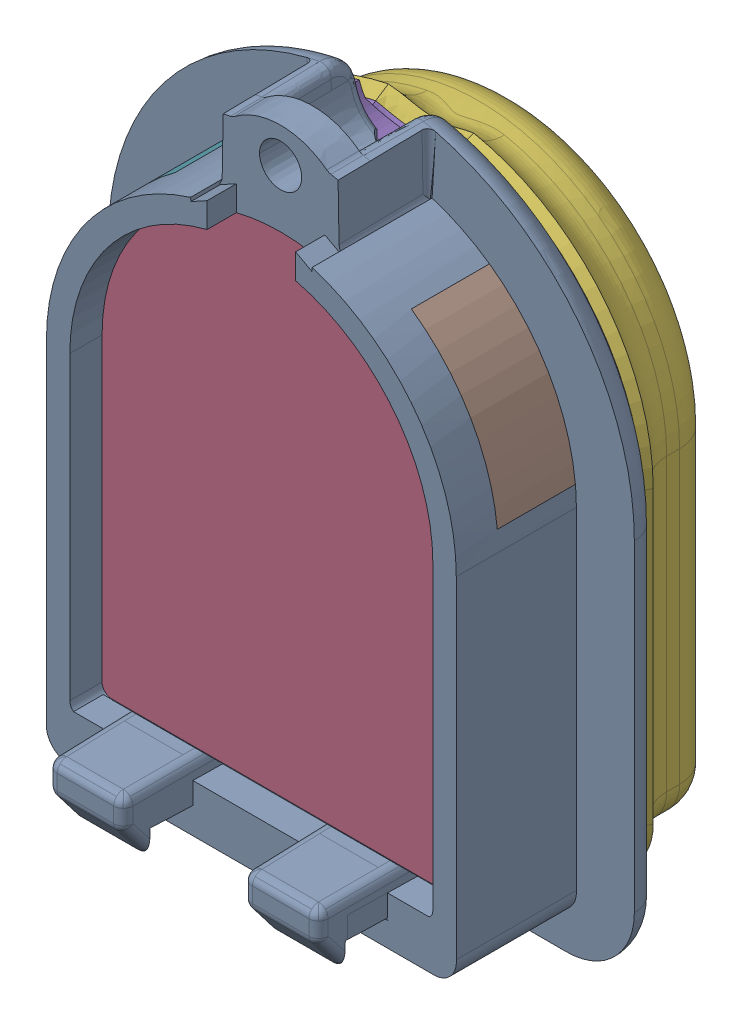
SolidWorks assembly Do2tDesign, configuration 默认. Lengths in mm.
Overall size (26.95 34.26 16.36).
9 component instances, 7 part files, 25 mates.
Components (placement in the parent):
- Dot2Tip1-1: Dot2Tip1 [默认] at (-1.9035 7.7463 -5.5591) size (26.95 34.26 11.2)
- Dot2lensnew-1: Dot2lensnew [默认] at (-1.9035 7.7463 -5.5591) size (18.6 25.2 6)
- Dot2Skin0.2-1: Dot2Skin0.2 [默认] at (-1.9035 7.4963 -5.5591) x (-1 0 0) z (0 0 -1) size (23.9 30.06 5.2)
- Dot2Skin1-1: Dot2Skin1 [默认] at (-1.9035 7.4963 -5.5591) x (-1 0 0) z (0 0 -1) size (22.77 29.32 5.25) (hidden)
- Dot2sidelens1-1: Dot2sidelens1 [默认] at (-1.9035 7.7463 -6.2091) size (6.4 7.71 4)
- Dot2sidelens1-2: Dot2sidelens1 [默认] at (-1.9035 7.7463 2.0909) x (-1 0 0) z (0 0 -1) size (6.4 7.71 4)
- Dot2bottomlens-1: Dot2bottomlens [默认] at (-5.9035 -10.5037 0.4409) x (1 0 0) z (0 1 0) size (8 4.5 2.35)
- Dot2DotMarker-1: Dot2DotMarker [默认] at (-7.9035 -5.4997 -10.2091) size (13 22 1)
- Dot2DotMarker-2: Dot2DotMarker [默认] at (-7.9035 -5.4997 -9.1991) size (13 22 1)
Mates (geometry in assembly coordinates):
- 同心1: concentric aligned: cylinder of Tip1-1 through (-1.9035 7.7463 51.2878) axis (0 0 -1) radius 9.3; cylinder of lensnew-1 through (-1.9035 7.7463 0.4409) axis (0 0 -1) radius 9.3
- 重合1: coincident anti-aligned: plane of Tip1-1 through (-1.9035 -8.1537 51.2878) normal (0 1 0); plane of lensnew-1 through (-11.2035 -8.1537 0.4409) normal (0 -1 0)
- 重合2: coincident aligned: plane of Tip1-1 through (-1.964 4.3089 -5.5591) normal (0 0 -1); plane of lensnew-1 through (-1.9035 7.7463 -5.5591) normal (0 0 -1)
- 重合3: coincident anti-aligned: plane of lensnew-1 through (-1.9035 7.7463 -5.5591) normal (0 0 -1); plane of Skin0.2-1 through (-1.9035 7.4963 -5.5591) normal (0 0 1)
- 同心2: concentric aligned: cone of Tip1-1 through (-1.9035 19.9963 -1.0591) axis (0 0 1); cylinder of Skin0.2-1 through (-1.9035 19.9963 -6.3091) axis (0 0 1) radius 2.75
- 宽度1: width aligned: plane of Skin0.2-1 through (-13.8535 7.4963 -5.5591) normal (-1 0 0); plane of Skin0.2-1 through (10.0465 7.4963 -5.5591) normal (1 0 0); plane of Tip1-1 through (-12.4035 7.7463 2.0909) normal (-1 0 0); plane of Tip1-1 through (8.5965 7.7463 2.0909) normal (1 0 0)
- 重合4: coincident anti-aligned: plane of Skin0.2-1 through (-1.9035 7.4963 -10.7591) normal (0 0 -1); plane of Skin1-1 through (-1.9035 7.4963 -10.7591) normal (0 0 1)
- 宽度2: width anti-aligned: plane of Skin0.2-1 through (-13.8535 7.4963 -5.5591) normal (-1 0 0); plane of Skin0.2-1 through (10.0465 7.4963 -5.5591) normal (1 0 0); plane of Skin1-1 through (-12.8325 0.0508 -6.2245) normal (-0.891007 0 0.45399); plane of Skin1-1 through (9.0255 0.0508 -6.2245) normal (0.891007 0 0.45399)
- 重合5: coincident aligned: cone of Skin0.2-1 through (-1.9035 7.4963 -6.2245) axis (0 0 1); cone of Skin1-1 through (-1.9035 7.4963 -6.2245) axis (0 0 1)
- 重合6: coincident anti-aligned: plane of Tip1-1 through (-16.7251 9.2061 -4.0591) normal (0.104528 0.994522 0); plane of sidelens1-1 through (8.4147 6.5638 -0.0591) normal (-0.104528 -0.994522 0)
- 重合7: coincident anti-aligned: plane of Tip1-1 through (-1.9035 7.7463 -4.0591) normal (0 0 1); plane of sidelens1-1 through (8.4147 6.5638 -4.0591) normal (0 0 -1)
- 同心3: concentric aligned: cylinder of Tip1-1 through (-1.9035 7.7463 2.0909) axis (0 0 -1) radius 10.5; cylinder of sidelens1-1 through (-1.9035 7.7463 -0.0591) axis (0 0 -1) radius 10.5
- 同心4: concentric anti-aligned: cylinder of Tip1-1 through (-1.9035 7.7463 2.0909) axis (0 0 -1) radius 10.5; cylinder of sidelens1-2 through (-1.9035 7.7463 -4.0591) axis (0 0 1) radius 10.5
- 重合8: coincident anti-aligned: plane of Tip1-1 through (12.0819 17.1622 -0.0591) normal (0.104528 -0.994522 0); plane of sidelens1-2 through (-13.0579 14.5199 -4.0591) normal (-0.104528 0.994522 0)
- 重合9: coincident anti-aligned: plane of Tip1-1 through (-1.9035 7.7463 -4.0591) normal (0 0 1); plane of sidelens1-2 through (-1.9035 7.7463 -4.0591) normal (0 0 -1)
- 重合10: coincident anti-aligned: plane of lensnew-1 through (-11.2035 -8.1537 0.4409) normal (0 -1 0); plane of bottomlens-1 through (-5.9035 -8.1537 0.4409) normal (0 1 0)
- 重合11: coincident anti-aligned: plane of Tip1-1 through (-5.9035 -18.1537 0.4409) normal (0 0 -1); plane of bottomlens-1 through (-5.9035 -8.1537 0.4409) normal (0 0 1)
- 重合12: coincident anti-aligned: plane of Tip1-1 through (2.0965 -18.1537 0.4409) normal (-1 0 0); plane of bottomlens-1 through (2.0965 -8.1537 0.4409) normal (1 0 0)
- 平行1: parallel anti-aligned: plane of lensnew-1 through (-1.9035 7.7463 -5.5591) normal (0 0 -1); plane of DotMarker-1 through (-7.9035 -5.4997 -10.2091) normal (0 0 1)
- 对称1: symmetric aligned: plane of Tip1-1 through (8.5965 7.7463 2.0909) normal (1 0 0); plane of DotMarker-1 through (-12.4035 7.7463 2.0909) normal (-1 0 0); plane of Tip1-1 through (-1.9035 -5.4997 -10.2091) normal (1 0 0)
- 距离1: distance = 14 mm anti-aligned: plane of DotMarker-1 through (-7.9035 3.5003 -10.2091) normal (0 1 0); plane of Tip1-1 through (-1.9035 -10.4997 2.0909) normal (0 -1 0)
- 距离2: distance = 0.55 mm anti-aligned: plane of DotMarker-1 through (-7.9035 -5.4997 -10.2091) normal (0 0 1); plane of Skin0.2-1 through (-1.9035 7.4963 -10.7591) normal (0 0 -1)
- 重合14: coincident aligned: plane of DotMarker-1 through (-1.9035 -5.4997 -10.2091) normal (1 0 0); plane of DotMarker-2 through (-1.9035 -5.4997 -9.1991) normal (1 0 0)
- 重合13: coincident aligned: plane of DotMarker-1 through (-7.9035 3.5003 -10.2091) normal (0 1 0); plane of DotMarker-2 through (-7.9035 3.5003 -9.1991) normal (0 1 0)
- 距离3: distance = 1.01 mm aligned: plane of DotMarker-2 through (-7.9035 -5.4997 -9.1991) normal (0 0 1); plane of DotMarker-1 through (-7.9035 -5.4997 -10.2091) normal (0 0 1)
